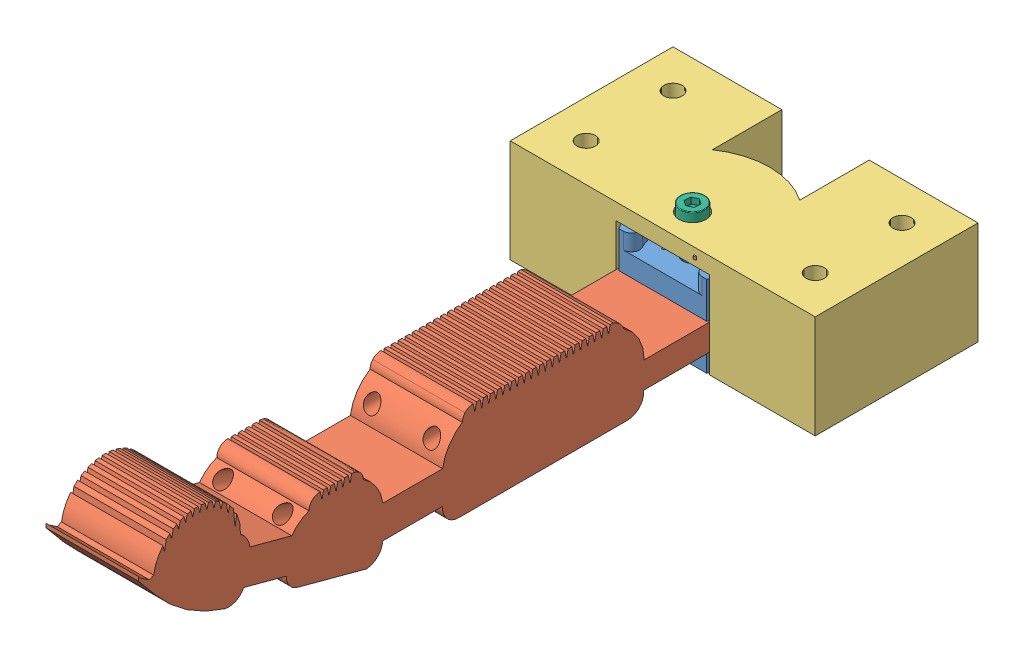
SolidWorks assembly fingerMoldAssembly, configuration Default. Lengths in mm.
Overall size (56.2 26.01 135.14).
8 component instances, 8 part files, 18 mates.
Components (placement in the parent):
- fingerBase-1: fingerBase [Default] at (11.0466 75.8139 30) x (0 0 1) z (-1 0 0) size (150 40 20) (hidden)
- fingerMold-1: fingerMold [Default] at (-5.9534 80.1189 39.9817) x (0 0 -1) z (1 0 0) size (107.08 28.43 18) (hidden)
- rotatingFingerLink-1: rotatingFingerLink [Default] at (-6.2534 86.0139 17.5) x (1 0 0) z (0 -1 0) size (19.58 15.29 15)
- fingerHDM-1: fingerHDM [Default] at (-6.6534 77.5139 30) x (0 0 -1) z (1 0 0) size (115.04 25.82 17)
- base-1: base [Default] at (29.9466 74.0139 30) x (-1 0 0) z (0 1 0) size (56.2 30 19)
- coilSpring-1: coilSpring [Default] at (1.8894 87.1034 24.4858) x (0.646126 -0.048213 0.761706) z (-0.753797 -0.196737 0.626965) size (10.32 5.71 10.53)
- hex thin nut chamfered gradeab_iso-1: hex thin nut chamfered gradeab_iso [ISO - 4035 - M2.5 - N] at (1.8466 75.6139 24.5) x (0.936336 0 -0.351105) z (0 1 0) size (5 5.77 1.6)
- socket head cap screw_iso-2: socket head cap screw_iso [ISO 4762 M2.5 x 12 - 12N] at (1.8466 94.5139 24.5) x (0 -1 0) z (0.996855 0 0.079246) size (14.5 4.5 4.5)
Mates (geometry in assembly coordinates):
- Coincident3: coincident anti-aligned: plane of fingerBase-1 through (11.0466 75.8139 30) normal (-1 0 0); plane of fingerMold-1 through (11.0466 92.1999 125.9368) normal (1 0 0)
- Coincident5: coincident anti-aligned: plane of fingerBase-1 through (9.0466 82.9139 41.6394) normal (0 -1 0); plane of fingerMold-1 through (10.0466 82.9139 39.9817) normal (0 1 0)
- Coincident7: coincident aligned: plane of fingerBase-1 through (27.9747 89.0139 30.5) normal (0 0 -1); plane of fingerMold-1 through (10.0466 80.1189 30.5) normal (0 0 -1)
- Concentric1: concentric aligned: cylinder of fingerBase-1 through (1.8466 73.5139 24.5) axis (0 1 0) radius 10.0404; cylinder of rotatingFingerLink-1 through (1.8466 74.0139 24.5) axis (0 1 0) radius 9.7908
- Coincident8: coincident anti-aligned: plane of fingerBase-1 through (27.9747 89.0139 14.7092) normal (0 -1 0); plane of rotatingFingerLink-1 through (1.8466 89.0139 24.5) normal (0 1 0)
- Coincident9: coincident anti-aligned: plane of rotatingFingerLink-1 through (9.8466 77.0139 20.1046) normal (0 0 1); plane of fingerHDM-1 through (10.3466 77.3139 20.1046) normal (0 0 -1)
- Distance1: distance = 0.5 mm anti-aligned: plane of rotatingFingerLink-1 through (9.8466 77.0139 22.3546) normal (-1 0 0); plane of fingerHDM-1 through (10.3466 77.2045 76.072) normal (1 0 0)
- Coincident11: coincident anti-aligned: plane of rotatingFingerLink-1 through (9.8466 77.5139 30) normal (0 1 0); plane of fingerHDM-1 through (10.3466 77.5139 24.6046) normal (0 -1 0)
- Distance2: distance = 1 mm anti-aligned: plane of base-1 through (29.9466 90.0139 30) normal (0 -1 0); plane of rotatingFingerLink-1 through (1.8466 89.0139 24.5) normal (0 1 0)
- Concentric2: concentric anti-aligned: cylinder of rotatingFingerLink-1 through (1.8466 74.0139 24.5) axis (0 1 0) radius 9.7908; cylinder of base-1 through (1.8466 90.0139 24.5) axis (0 -1 0) radius 10.2
- Coincident14: coincident aligned: plane of rotatingFingerLink-1 through (-6.2534 74.0139 30) normal (0 0 1); plane of base-1 through (-5.8793 90.0139 30) normal (0 0 1)
- Tangent1: tangent: cylinder of rotatingFingerLink-1 through (-5.4155 89.0139 28.5) axis (0 -1 0) radius 1.5; circle of coilSpring-1
- Concentric3: concentric aligned: cylinder of rotatingFingerLink-1 through (1.8466 74.0139 24.5) axis (0 1 0) radius 1.8; cylinder of hex thin nut chamfered gradeab_iso-1 through (1.8466 74.0139 24.5) axis (0 1 0) radius 1.025
- Coincident15: coincident aligned: plane of rotatingFingerLink-1 through (1.8466 74.0139 24.5) normal (0 -1 0); plane of hex thin nut chamfered gradeab_iso-1 through (0.833 74.0139 21.797) normal (0 -1 0)
- Concentric6: concentric anti-aligned: cylinder of base-1 through (1.8466 97.8223 24.5) axis (0 -1 0) radius 1.2; cylinder of socket head cap screw_iso-2 through (1.8466 126.2639 24.5) axis (0 1 0) radius 1.25
- Parallel2: parallel anti-aligned: plane of fingerBase-1 through (27.9747 89.0139 30.5) normal (0 0 -1); plane of base-1 through (-5.8793 90.0139 30) normal (0 0 1)
- Coincident19: coincident anti-aligned: plane of base-1 through (1.8466 92.0139 24.5) normal (0 1 0); plane of socket head cap screw_iso-2 through (2.0249 92.0139 22.2571) normal (0 -1 0)
- Coincident20: coincident anti-aligned: plane of base-1 through (29.9466 90.0139 0) normal (0 0 -1); plane of assembly through (0 0 0) normal (0 0 1)
